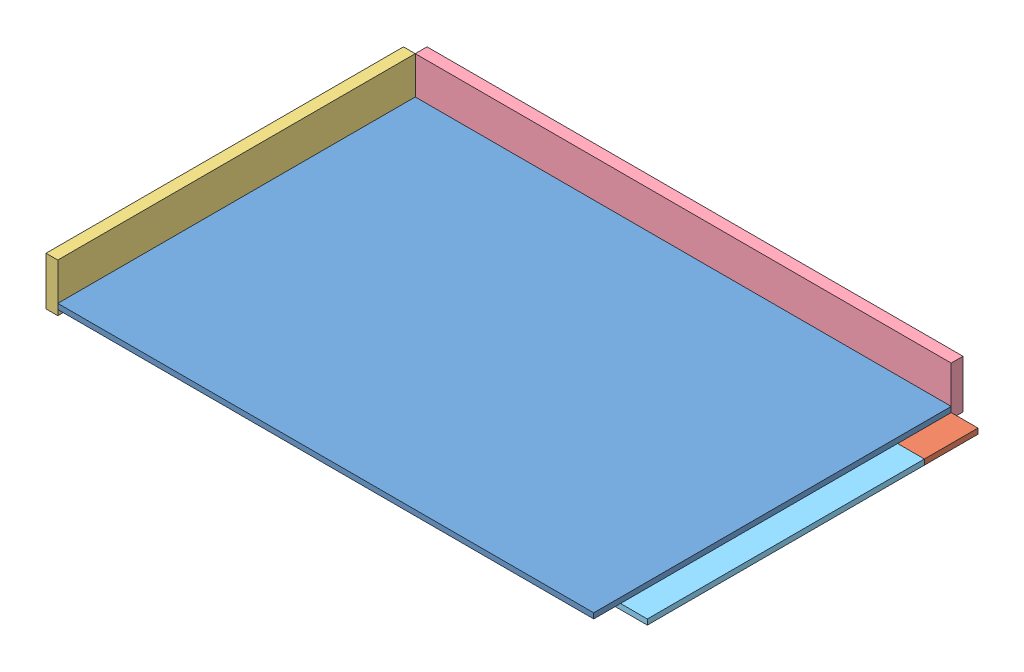
SolidWorks assembly Terrain_9_Partie_1, configuration Défaut. Lengths in mm.
Overall size (1072 90 689).
6 component instances, 5 part files, 15 mates.
Components (placement in the parent):
- planche_1000x667x10-1: planche_1000x667x10 [Default] at (-487.8705 6.0268 333.5) size (1000 10 667)
- planche_1050x100x10-1: planche_1050x100x10 [Default] at (-487.8705 -3.9732 -233.5) size (1050 10 100)
- planche_667x90x22-1: planche_667x90x22 [Default] at (-509.8705 -3.9732 333.5) x (0 0 -1) z (1 0 0) size (667 90 22)
- planche_1000x90x22-1: planche_1000x90x22 [Default] at (-487.8705 -3.9732 -355.5) size (1000 90 22)
- planche_517x100x10-1: planche_517x100x10 [Default] at (562.1295 -3.9732 283.5) x (0 0 -1) z (1 0 0) size (517 10 100)
- planche_517x100x10-2: planche_517x100x10 [Default] at (-387.8705 -3.9732 283.5) x (0 0 -1) z (1 0 0) size (517 10 100)
Mates (geometry in assembly coordinates):
- Coïncidente1: coincident anti-aligned: plane of planche_1000x667x10-1 through (-487.8705 6.0268 -333.5) normal (0 -1 0); plane of planche_1050x100x10-1 through (-487.8705 6.0268 -333.5) normal (0 1 0)
- Coïncidente2: coincident aligned: plane of planche_1000x667x10-1 through (-487.8705 16.0268 333.5) normal (-1 0 0); plane of planche_1050x100x10-1 through (-487.8705 6.0268 -233.5) normal (-1 0 0)
- Coïncidente3: coincident aligned: plane of planche_1000x667x10-1 through (-487.8705 16.0268 -333.5) normal (0 0 -1); plane of planche_1050x100x10-1 through (-487.8705 6.0268 -333.5) normal (0 0 -1)
- Coïncidente4: coincident anti-aligned: plane of planche_1000x667x10-1 through (-487.8705 16.0268 333.5) normal (-1 0 0); plane of planche_667x90x22-1 through (-487.8705 86.0268 333.5) normal (1 0 0)
- Coïncidente5: coincident aligned: plane of planche_1050x100x10-1 through (-487.8705 -3.9732 -333.5) normal (0 -1 0); plane of planche_667x90x22-1 through (-487.8705 -3.9732 333.5) normal (0 -1 0)
- Coïncidente6: coincident aligned: plane of planche_1050x100x10-1 through (-487.8705 6.0268 -333.5) normal (0 0 -1); plane of planche_667x90x22-1 through (-487.8705 -3.9732 -333.5) normal (0 0 -1)
- Coïncidente7: coincident anti-aligned: plane of planche_1000x667x10-1 through (-487.8705 16.0268 -333.5) normal (0 0 -1); plane of planche_1000x90x22-1 through (-487.8705 86.0268 -333.5) normal (0 0 1)
- Coïncidente8: coincident aligned: plane of planche_1050x100x10-1 through (-487.8705 -3.9732 -333.5) normal (0 -1 0); plane of planche_1000x90x22-1 through (-487.8705 -3.9732 -333.5) normal (0 -1 0)
- Coïncidente9: coincident anti-aligned: plane of planche_667x90x22-1 through (-487.8705 86.0268 333.5) normal (1 0 0); plane of planche_1000x90x22-1 through (-487.8705 -3.9732 -333.5) normal (-1 0 0)
- Coïncidente10: coincident anti-aligned: plane of planche_1000x667x10-1 through (-487.8705 6.0268 -333.5) normal (0 -1 0); plane of ? through (-721.9683 6.0268 283.5) normal (0 1 0)
- Coïncidente11: coincident anti-aligned: plane of planche_1000x667x10-1 through (-487.8705 6.0268 -333.5) normal (0 -1 0); plane of planche_517x100x10-1 through (462.1295 6.0268 283.5) normal (0 1 0)
- Coïncidente12: coincident anti-aligned: plane of planche_1050x100x10-1 through (-487.8705 6.0268 -233.5) normal (0 0 1); plane of planche_517x100x10-1 through (562.1295 6.0268 -233.5) normal (0 0 -1)
- Coïncidente13: coincident aligned: plane of planche_1050x100x10-1 through (562.1295 6.0268 -233.5) normal (1 0 0); plane of planche_517x100x10-1 through (562.1295 6.0268 283.5) normal (1 0 0)
- Coïncidente14: coincident anti-aligned: plane of planche_1050x100x10-1 through (-487.8705 6.0268 -233.5) normal (0 0 1); plane of ? through (-621.9683 6.0268 -233.5) normal (0 0 -1)
- Coïncidente15: coincident anti-aligned: plane of planche_667x90x22-1 through (-487.8705 86.0268 333.5) normal (1 0 0); plane of ? through (-721.9683 6.0268 283.5) normal (-1 0 0)
